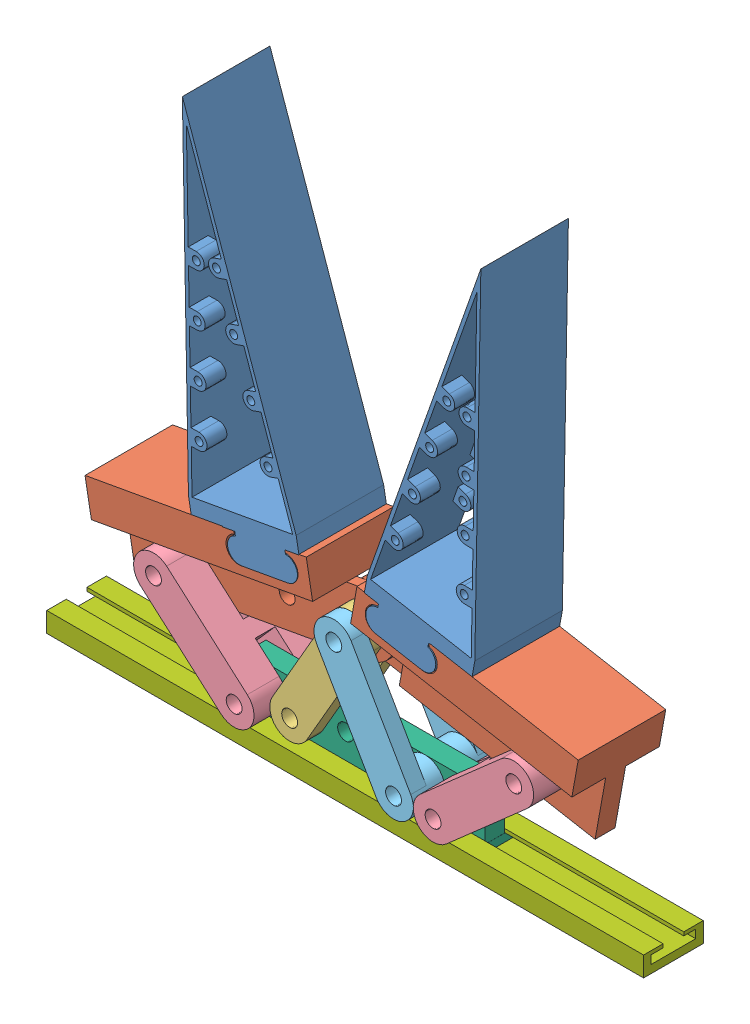
SolidWorks assembly sw-hand-assembly, configuration Default. Lengths in mm.
Overall size (150 139.74 77.03).
12 component instances, 7 part files, 25 mates.
Components (placement in the parent):
- Gripper-2: Gripper [Default] at (42.86 52.4832 62.323) x (0.984189 -0.177124 0) z (0 0 1) size (27.5 95.86 22)
- Platte-2: Platte [Default] at (51.9897 3.3313 53.823) x (0.984189 -0.177124 0) z (0.177124 0.984189 0) size (67.5 22 24)
- Platte-3: Platte [Default] at (28.5522 3.3313 48.823) x (-0.984189 -0.177124 0) z (-0.177124 0.984189 0) size (67.5 22 24)
- Gripper-3: Gripper [Default] at (37.6818 52.4832 40.323) x (-0.984189 -0.177124 0) z (0 0 -1) size (27.5 95.86 22)
- Arm2-1: Arm2 [Default] at (62.6559 1.4178 44.873) x (0.5 0.866025 0) z (-0.866025 0.5 0) size (40 13 10)
- Arm-1: Arm [Default] at (33.1636 44.7993 61.823) x (-0.75084 0.660484 0) z (-0.660484 -0.75084 0) size (37 21 10)
- Arm1-1: Arm1 [Default] at (82.2814 38.5965 40.973) x (-0.5 0.866025 0) z (-0.866025 -0.5 0) size (40 8 10)
- Arm1-2: Arm1 [Default] at (17.886 1.4178 61.773) x (-0.5 0.866025 0) z (0.866025 0.5 0) size (40 8 10)
- Arm-2: Arm [Default] at (96.4902 -11.0312 61.823) x (0.75084 0.660484 0) z (-0.660484 0.75084 0) size (37 21 10)
- Schiene-1: Schiene [Default] at (47.4422 -6.9666 53.823) x (1 0 0) z (0 1 0) size (30 11 14.02)
- Schiene-2: Schiene [Default] at (17.4422 -6.9666 53.823) x (1 0 0) z (0 1 0) size (30 11 14.02)
- Nut-1: Nut [Default] at (-34.7291 -1.9214 39.5484) x (0 0 1) z (0 1 0) size (33.29 150 5)
Mates (geometry in assembly coordinates):
- Coincident8: coincident aligned: plane of Gripper-2 through (63.4482 45.533 62.323) normal (0 0 1); plane of Platte-2 through (102.2448 42.615 62.323) normal (0 0 1)
- Coincident10: coincident anti-aligned: plane of Gripper-2 through (51.3034 44.6704 40.323) normal (-0.177124 -0.984189 0); plane of Platte-2 through (51.3034 44.6704 -12.6186) normal (0.177124 0.984189 0)
- Coincident11: coincident aligned: line of Gripper-2 through (51.3034 44.6704 40.323) axis (0 0 1); line of Platte-2 through (51.3034 44.6704 40.323) axis (0 0 1)
- Coincident12: coincident anti-aligned: circle of Platte-2; circle of Platte-3
- Coincident13: coincident aligned: plane of Platte-3 through (-21.7029 42.615 40.323) normal (0 0 -1); plane of Gripper-3 through (17.0937 45.533 40.323) normal (0 0 -1)
- Coincident14: coincident aligned: line of Platte-3 through (17.4282 42.545 40.323) axis (0.984189 0.177124 0); line of Gripper-3 through (17.625 42.5804 40.323) axis (0.984189 0.177124 0)
- Coincident15: coincident aligned: line of Platte-3 through (29.2385 44.6704 62.323) axis (0 0 -1); line of Gripper-3 through (29.2385 44.6704 62.323) axis (0 0 -1)
- Coincident16: coincident aligned: circle of Platte-2; circle of Arm2-1
- Coincident17: coincident aligned: circle of Platte-3; circle of Arm-1
- Coincident18: coincident aligned: circle of Arm2-1; circle of Arm1-1
- Coincident19: coincident anti-aligned: circle of Arm2-1; circle of Arm1-2
- Coincident20: coincident anti-aligned: circle of Platte-2; circle of Arm-2
- Concentric3: concentric aligned: circle of Arm-2; circle of Schiene-1
- Concentric4: concentric aligned: cylinder of Arm1-1 through (55.2709 11.0226 40.973) axis (0 0 1) radius 2; cylinder of Schiene-1 through (55.2709 11.0226 21.1274) axis (0 0 1) radius 2
- Concentric5: concentric anti-aligned: cylinder of Arm1-2 through (55.2709 11.0226 61.773) axis (0 0 -1) radius 2; cylinder of Schiene-1 through (55.2709 11.0226 21.1274) axis (0 0 1) radius 2
- Coincident22: coincident anti-aligned: plane of Arm-2 through (87.0798 -21.34 48.823) normal (0 0 1); plane of Schiene-1 through (47.4422 -6.9666 48.823) normal (0 0 -1)
- Coincident23: coincident anti-aligned: plane of Arm-1 through (34.8273 45.3666 53.823) normal (0 0 -1); plane of Schiene-2 through (17.4422 -6.9666 53.823) normal (0 0 1)
- Concentric8: concentric anti-aligned: cylinder of Arm-1 through (15.2709 11.0226 61.823) axis (0 0 -1) radius 2; cylinder of Schiene-2 through (15.2709 11.0226 21.1274) axis (0 0 1) radius 2
- Concentric9: concentric aligned: cylinder of Arm2-1 through (25.2709 11.0226 44.873) axis (0 0 1) radius 2; cylinder of Schiene-2 through (25.2709 11.0226 21.1274) axis (0 0 1) radius 2
- Coincident36: coincident anti-aligned: plane of Nut-1 through (115.2709 0 43.923) normal (0 -1 0); plane of assembly through (0 0 0) normal (0 1 0)
- Coincident38: coincident anti-aligned: line of Schiene-1 through (40.2709 2 45.823) axis (1 0 0); line of Nut-1 through (115.2709 2 45.823) axis (-1 0 0)
- Coincident39: coincident anti-aligned: line of Schiene-2 through (10.2709 2 45.823) axis (1 0 0); line of Nut-1 through (115.2709 2 45.823) axis (-1 0 0)
- Coincident42: coincident anti-aligned: plane of Schiene-2 through (10.2709 2 45.823) normal (0 -1 0); plane of Nut-1 through (115.2709 2 57.023) normal (0 1 0)
- Coincident43: coincident anti-aligned: line of Schiene-2 through (40.2709 2 45.823) axis (0 0 1); line of Nut-1 through (40.2709 2 67.027) axis (0 0 -1)
- Coincident44: coincident anti-aligned: line of Schiene-1 through (40.2709 2 45.823) axis (0 0 1); line of Nut-1 through (40.2709 2 67.027) axis (0 0 -1)
